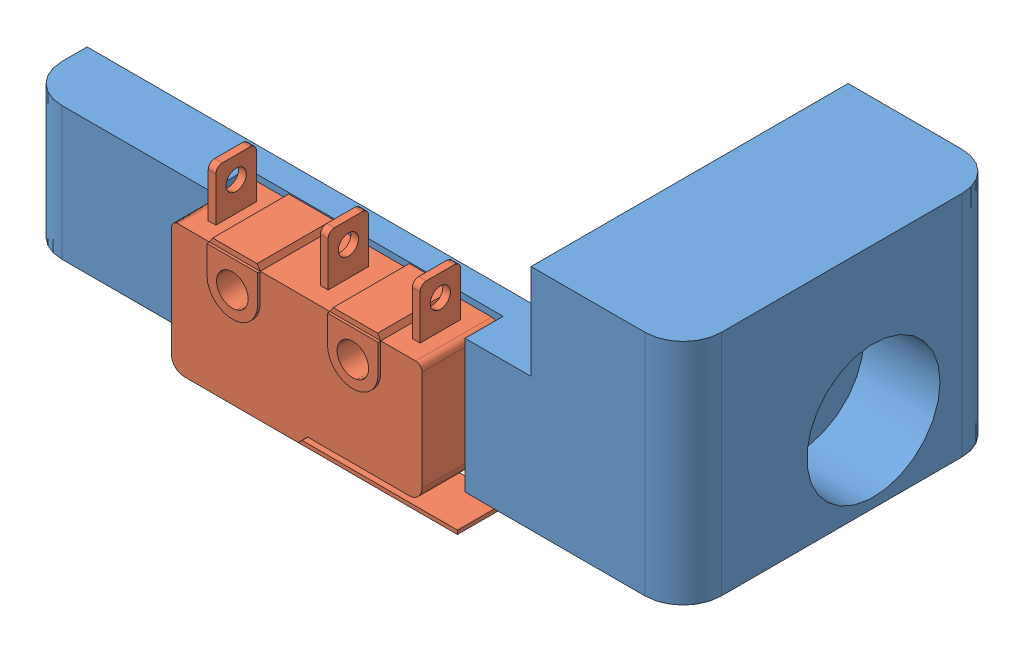
SolidWorks assembly Assem-end stop holder-V3, configuration Default. Lengths in mm.
Overall size (52 19 28.4).
2 component instances, 2 part files, 3 mates.
Components (placement in the parent):
- PlasPrint-End Stop Holder-V3-1: PlasPrint-End Stop Holder-V3 [Default] at (27.5778 16.7515 38.7026) size (52 18 25)
- Part-Radio Shack-Endstop-275-0016-1: Part-Radio Shack-Endstop-275-0016 [Default] at (12.2602 21.8295 43.9026) x (1 0 0) z (0 -1 0) size (21.55 6.4 15.2)
Mates (geometry in assembly coordinates):
- Coincident1: coincident anti-aligned: plane of PlasPrint-End Stop Holder-V3-1 through (27.5778 16.7515 40.7026) normal (0 0 1); plane of Part-Radio Shack-Endstop-275-0016-1 through (16.9278 24.7742 40.7026) normal (0 0 -1)
- Coincident2: coincident aligned: plane of PlasPrint-End Stop Holder-V3-1 through (27.5778 16.7515 40.7026) normal (0 -1 0); plane of Part-Radio Shack-Endstop-275-0016-1 through (3.4278 16.7515 40.9026) normal (0 -1 0)
- Width1: width anti-aligned: plane of PlasPrint-End Stop Holder-V3-1 through (2.2278 27.2515 43.7026) normal (1 0 0); plane of Part-Radio Shack-Endstop-275-0016-1 through (22.3778 27.2515 43.7026) normal (-1 0 0); plane of PlasPrint-End Stop Holder-V3-1 through (2.4278 17.7515 40.9026) normal (-1 0 0); plane of Part-Radio Shack-Endstop-275-0016-1 through (22.1778 18.5015 40.9026) normal (1 0 0)
